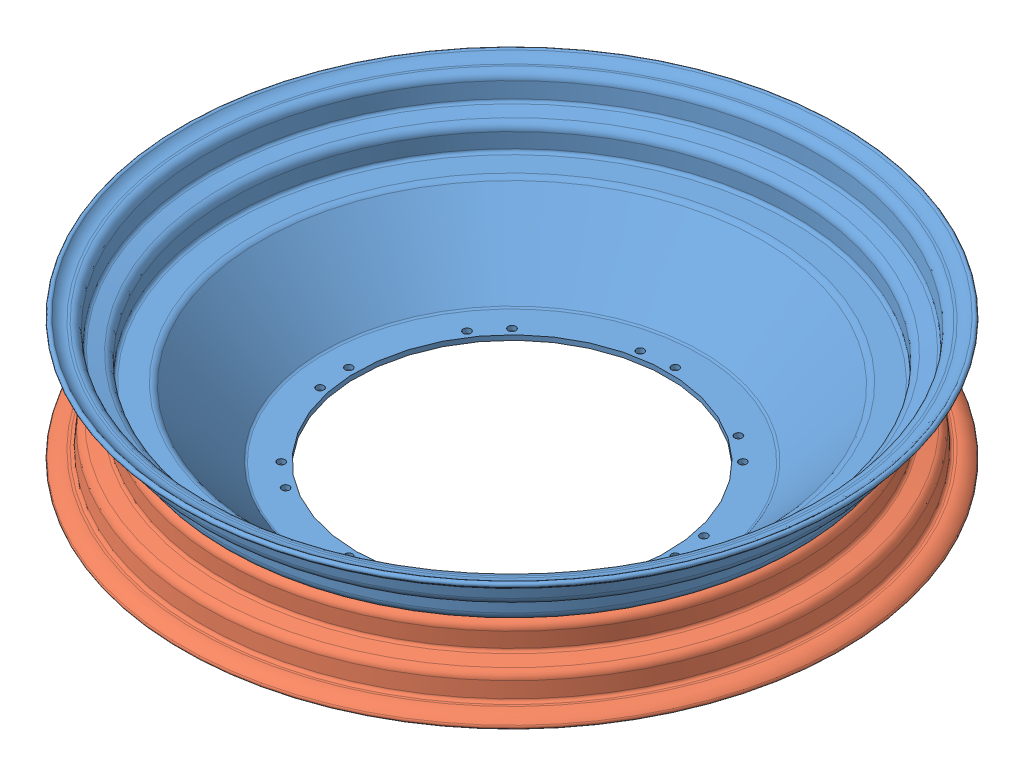
SolidWorks assembly Assem1+2, configuration Default. Lengths in mm.
Overall size (598 86.66 598).
2 component instances, 2 part files, 2 mates.
Components (placement in the parent):
- spun wheel125-1-1: spun wheel125-1 [Default] at origin size (432.05 86.66 432.05)
- spun wheel125-2-1: spun wheel125-2 [Default] x (0.837169 0 0.546944) z (0.546944 0 -0.837169) size (432.05 41.65 432.05)
Mates (geometry in assembly coordinates):
- Distance1: distance = 0 mm: cylinder of spun wheel125-2-1 through (0 -240.889 0) axis (0 -1 0) radius 188.0539; cylinder of spun wheel125-1-1 through (0 240.889 0) axis (0 1 0) radius 188.0539
- Coincident2: coincident anti-aligned: plane of spun wheel125-1-1 through (-182.8739 0 0) normal (0 -1 0); plane of spun wheel125-2-1 through (-153.0964 0 -100.0218) normal (0 1 0)
